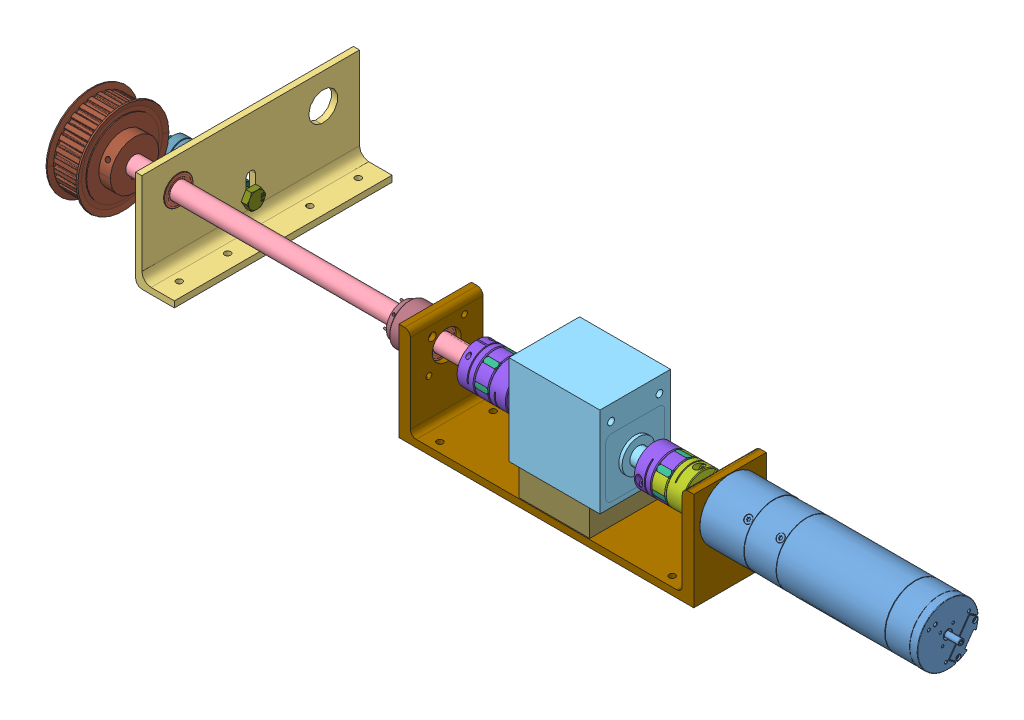
SolidWorks assembly motor assm2, configuration Default. Lengths in mm.
Overall size (903.62 127.5 242.79).
29 component instances, 17 part files, 53 mates.
Components (placement in the parent):
- motor v1-1: motor v1 [Default] at (-10.682 -0.6 0) x (1 0 0) z (0 -0.707107 0.707107) size (278.16 78.2 78.2)
- vbx_18mmID_bearing-1: vbx_18mmID_bearing [5972K329] at (-306.982 -0.6 0) x (0 0 1) z (1 0 0) size (30 30 7)
- vbx_18mmID_bearing-2: vbx_18mmID_bearing [5972K329] at (-304.0556 -36.1833 21.8955) x (0 0.990942 0.13429) z (-1 0 0) size (30 30 7)
- vbx_18mmID_bearing-3: vbx_18mmID_bearing [5972K329] at (-578.9992 -0.6 0) x (0 -0.254277 0.967131) z (1 0 0) size (30 30 7)
- bearing mount-3: bearing mount [Default] at (-582.4992 -70.6 -187.5) x (0 0 1) z (-1 0 0) size (225 101.6 40)
- 1439K370_1045 CARBON STEEL KEYED ROTARY SHAFT-1: 1439K370_1045 CARBON STEEL KEYED ROTARY SHAFT [1439K37] at (-457.6492 -0.6 0) x (0 0 1) z (1 0 0) size (18 17.49 425)
- Torque sensor-1: Torque sensor [Default] at (-150.7086 -0.6 0) x (0 0 -1) z (1 0 0) size (73 93 168)
- 15-18mm Misalinemnt coupler-1: 15-18mm Misalinemnt coupler [Default] at (-34.8408 -7.0529 -26.7672) x (0 -0.707107 0.707107) z (-1 0 0) size (41.3 42.02 51.03)
  - 9845T210_VIBRATE-DAMPING PRECISION FLEXIBLE SHAFT CPLG-1: 9845T210_VIBRATE-DAMPING PRECISION FLEXIBLE SHAFT CPLG [9845T21] at (14.3644 23.4902 31.8678) size (38.38 42 16.93)
  - 9845T469_VIBRATE-DAMPING PRECISION FLEXIBLE SHAFT COUPLING-1: 9845T469_VIBRATE-DAMPING PRECISION FLEXIBLE SHAFT COUPLING [9845T469] at (14.3644 23.4902 25.3411) size (41.3 41.3 33.46)
  - 9845T471_VIBRATE-DAMPING PRECISION FLEXIBLE SHAFT COUPLING-1: 9845T471_VIBRATE-DAMPING PRECISION FLEXIBLE SHAFT COUPLING [9845T471] at (14.3644 23.4902 23.3678) x (-1 0 0) z (0 0 -1) size (41.3 41.3 33.46)
- 1630T721_MULTIPURPOSE 6061 ALUMINUM U-CHANNEL-1: 1630T721_MULTIPURPOSE 6061 ALUMINUM U-CHANNEL [1630T721] at (-158.082 -70.6 0) size (304.8 101.6 75)
- 18-18mm Misalinemnt coupler-1: 18-18mm Misalinemnt coupler [Default] at (-266.5764 13.7644 23.4902) x (0 -1 0) z (1 0 0) size (41.3 42.02 51.03)
  - 9845T210_VIBRATE-DAMPING PRECISION FLEXIBLE SHAFT CPLG-1: 9845T210_VIBRATE-DAMPING PRECISION FLEXIBLE SHAFT CPLG [9845T21] at (14.3644 23.4902 31.8678) size (38.38 42 16.93)
  - 9845T471_VIBRATE-DAMPING PRECISION FLEXIBLE SHAFT COUPLING-1: 9845T471_VIBRATE-DAMPING PRECISION FLEXIBLE SHAFT COUPLING [9845T471] at (14.3644 23.4902 23.3678) x (-1 0 0) z (0 0 -1) size (41.3 41.3 33.46)
  - 9845T471_VIBRATE-DAMPING PRECISION FLEXIBLE SHAFT COUPLING-2: 9845T471_VIBRATE-DAMPING PRECISION FLEXIBLE SHAFT COUPLING [9845T471] at (14.3644 23.4902 25.3411) size (41.3 41.3 33.46)
- Encoder v1-1: Encoder v1 [Default] at (-285.7992 -0.6 0) x (0 -0.379337 0.925259) z (-1 0 0) size (50.8 52.34 36.53) (hidden)
- 28tooth-1: 28tooth [Default] at (-665.1492 -0.6 0) x (1 0 0) z (0 0 -1) size (44.41 95 95) (flexible)
  - ATPA28L100_B_N18_3-1: ATPA28L100_B_N18_3 [Default] at (38 -4.5 -7.7942) x (0 0.5 0.866025) z (-1 0 0) size (5 6 6)
  - ATPA28L100_B_N18_3-2: ATPA28L100_B_N18_3 [Default] at (38 11.8 0) x (0 -1 0) z (-1 0 0) size (5 6 6)
  - ATPA28L100_B_N18_6-1: ATPA28L100_B_N18_6 [Default] at origin size (44.41 95 95)
- Torque sensor spacer-1: Torque sensor spacer [Default] at (-150.7086 -36.1 0) x (-1 0 0) z (0 0 1) size (73 27.73 73)
- Through Hole Slip ring H2042-06s-1: Through Hole Slip ring H2042-06s [Default] at (-330.4544 -0.6 0) x (1 0 0) z (0 0.707107 0.707107) size (51.5 61 42)
- 5972K326_BALL BEARING-1: 5972K326_BALL BEARING [5972K326] at (-642.6055 -43.725 -75) x (0 -0.044078 -0.999028) z (1 0 0) size (30 30 9)
- 90593A008_BLACK-OXIDE STEEL HEX NUT-1: 90593A008_BLACK-OXIDE STEEL HEX NUT [90593A008] at (-586.4992 -43.725 -75) x (0 1 0) z (0 0 1) size (17 8 19.63)
- 91310A139_HIGH-STRG UNCOATED STL CAP SCREW - CLASS 10.9-1: 91310A139_HIGH-STRG UNCOATED STL CAP SCREW - CLASS 10.9 [91310A139] at (-617.9492 -43.725 -75) x (-1 0 0) z (0 -1 0) size (96.4 19.63 17)
- 90593A008_BLACK-OXIDE STEEL HEX NUT-2: 90593A008_BLACK-OXIDE STEEL HEX NUT [90593A008] at (-634.1055 -43.725 -75) x (0 1 0) z (0 0 1) size (17 8 19.63)
- 90593A008_BLACK-OXIDE STEEL HEX NUT-3: 90593A008_BLACK-OXIDE STEEL HEX NUT [90593A008] at (-660.1055 -43.725 -75) x (0 -0.5 0.866025) z (0 0.866025 0.5) size (17 8 19.63)
- 5972K326_BALL BEARING-2: 5972K326_BALL BEARING [5972K326] at (-651.6055 -43.725 -75) x (0 -0.044078 -0.999028) z (1 0 0) size (30 30 9)
Mates (geometry in assembly coordinates):
- Concentric25: concentric anti-aligned: cylinder of vbx_18mmID_bearing-1 through (-303.482 -0.6 0) axis (1 0 0) radius 9; cylinder of 1439K611_1045 CARBON STEEL KEYED ROTARY SHAFT (1)-1 through (-34.75 0 0) axis (-1 0 0) radius 10
- Parallel10: parallel anti-aligned: plane of vbx_18mmID_bearing-1 through (-306.982 -0.6 0) normal (0 -1 0); plane of 1439K611_1045 CARBON STEEL KEYED ROTARY SHAFT (1)-1 through (-334.75 -3 10) normal (0 1 0)
- Concentric26: concentric anti-aligned: cylinder of 1439K611_1045 CARBON STEEL KEYED ROTARY SHAFT (1)-1 through (-34.75 0 0) axis (-1 0 0) radius 10; cylinder of timming belt pully-1/timing belt pully face-2 through (-119.9209 0 0) axis (1 0 0) radius 10
- Parallel12: parallel anti-aligned: plane of 1439K611_1045 CARBON STEEL KEYED ROTARY SHAFT (1)-1 through (-334.75 -3 10) normal (0 1 0); plane of timming belt pully-1/timing belt pully face-1 through (-158.0209 -2.95 0) normal (0 -1 0)
- Concentric30: concentric aligned: cylinder of 1439K611_1045 CARBON STEEL KEYED ROTARY SHAFT (1)-1 through (-34.75 0 0) axis (-1 0 0) radius 10; cylinder of vbx_18mmID_bearing-2 through (-307.5556 -36.1833 21.8955) axis (-1 0 0) radius 9
- Coincident43: coincident aligned: plane of vbx_18mmID_bearing-3 through (-582.4992 -14.7685 -3.7252) normal (-1 0 0); plane of bearing mount-3 through (-582.4992 -70.6 37.5) normal (-1 0 0)
- Concentric38: concentric aligned: cylinder of motor v1-1 through (-15.882 -0.6 0) axis (-1 0 0) radius 7.5; cylinder of 1439K370_1045 CARBON STEEL KEYED ROTARY SHAFT-1 through (-245.1492 -0.6 0) axis (-1 0 0) radius 9
- Concentric39: concentric aligned: cylinder of motor v1-1 through (-15.882 -0.6 0) axis (-1 0 0) radius 7.5; cylinder of Torque sensor-1 through (-66.7086 -0.6 0) axis (-1 0 0) radius 9
- Parallel13: parallel aligned: plane of Torque sensor-1 through (-103.7086 56.9 36.5) normal (0 0 1)
- Concentric50: concentric anti-aligned: cylinder of motor v1-1 through (-15.882 -0.6 0) axis (-1 0 0) radius 7.5; cylinder of 15-18mm Misalinemnt coupler-1/9845T469_VIBRATE-DAMPING PRECISION FLEXIBLE SHAFT COUPLING-1 through (-78.682 -0.6 0) axis (1 0 0) radius 7.5
- Coincident48: coincident anti-aligned: plane of motor v1-1 through (-39.182 -7.6711 3.5355) normal (0 -0.707107 -0.707107); plane of 15-18mm Misalinemnt coupler-1/9845T469_VIBRATE-DAMPING PRECISION FLEXIBLE SHAFT COUPLING-1 through (-33.682 -8.2368 4.1012) normal (0 0.707107 0.707107)
- Coincident49: coincident aligned: plane of 15-18mm Misalinemnt coupler-1/9845T469_VIBRATE-DAMPING PRECISION FLEXIBLE SHAFT COUPLING-1 through (-44.682 -0.6 -29.2035) normal (-1 0 0); plane of motor v1-1 through (-44.682 2.087 2.687) normal (-1 0 0)
- Coincident50: coincident aligned: plane of Torque sensor-1 through (-66.7086 -0.6 0) normal (1 0 0); plane of 15-18mm Misalinemnt coupler-1/9845T471_VIBRATE-DAMPING PRECISION FLEXIBLE SHAFT COUPLING-1 through (-66.7086 -0.6 0) normal (1 0 0)
- Concentric51: concentric aligned: cylinder of motor v1-1 through (-7.932 -0.6 0) axis (1 0 0) radius 20; cylinder of 1630T721_MULTIPURPOSE 6061 ALUMINUM U-CHANNEL-1 through (-26.682 -0.6 0) axis (1 0 0) radius 21
- Concentric52: concentric aligned: cylinder of motor v1-1 through (0.818 17.7848 18.3848) axis (-1 0 0) radius 2.067; cylinder of 1630T721_MULTIPURPOSE 6061 ALUMINUM U-CHANNEL-1 through (-17.62 17.7848 18.3848) axis (-1 0 0) radius 2.65
- Concentric53: concentric aligned: cylinder of vbx_18mmID_bearing-1 through (-303.482 -0.6 0) axis (1 0 0) radius 15; cylinder of 1630T721_MULTIPURPOSE 6061 ALUMINUM U-CHANNEL-1 through (-319.544 -0.6 0) axis (1 0 0) radius 15
- Coincident54: coincident anti-aligned: plane of motor v1-1 through (-5.682 -18.808 18.208) normal (-1 0 0); plane of 1630T721_MULTIPURPOSE 6061 ALUMINUM U-CHANNEL-1 through (-5.682 -70.6 37.5) normal (1 0 0)
- Coincident55: coincident aligned: plane of vbx_18mmID_bearing-1 through (-310.482 -15.25 0) normal (-1 0 0); plane of 1630T721_MULTIPURPOSE 6061 ALUMINUM U-CHANNEL-1 through (-310.482 31 37.5) normal (-1 0 0)
- Concentric54: concentric anti-aligned: cylinder of Torque sensor-1 through (-234.7086 -0.6 0) axis (1 0 0) radius 9; cylinder of 18-18mm Misalinemnt coupler-1/9845T471_VIBRATE-DAMPING PRECISION FLEXIBLE SHAFT COUPLING-1 through (-216.7086 -0.6 0) axis (-1 0 0) radius 9
- Coincident56: coincident aligned: plane of Torque sensor-1 through (-234.7086 -0.6 0) normal (-1 0 0); plane of 18-18mm Misalinemnt coupler-1/9845T471_VIBRATE-DAMPING PRECISION FLEXIBLE SHAFT COUPLING-1 through (-234.7086 -0.6 0) normal (-1 0 0)
- Coincident57: coincident aligned: plane of Torque sensor-1 through (-150.7086 5.4 -3) normal (0 0 1); plane of 18-18mm Misalinemnt coupler-1/9845T471_VIBRATE-DAMPING PRECISION FLEXIBLE SHAFT COUPLING-1 through (-216.7086 10.6853 -3) normal (0 0 1)
- Concentric55: concentric anti-aligned: cylinder of vbx_18mmID_bearing-1 through (-303.482 -0.6 0) axis (1 0 0) radius 9; cylinder of Encoder v1-1 through (-261.0342 -0.6 0) axis (-1 0 0) radius 7.5006
- Concentric56: concentric anti-aligned: cylinder of 1439K370_1045 CARBON STEEL KEYED ROTARY SHAFT-1 through (-245.1492 -0.6 0) axis (-1 0 0) radius 9; cylinder of 28tooth-1/ATPA28L100_B_N18_6-1 through (-621.1492 -0.6 0) axis (1 0 0) radius 9
- Coincident59: coincident aligned: plane of 1439K370_1045 CARBON STEEL KEYED ROTARY SHAFT-1 through (-670.1492 -9.6 3) normal (0 0 -1); plane of 28tooth-1/ATPA28L100_B_N18_6-1 through (-621.1492 -0.6 3) normal (0 0 -1)
- Coincident61: coincident anti-aligned: plane of Torque sensor-1 through (-103.7086 -36.1 36.5) normal (0 -1 0); plane of Torque sensor spacer-1 through (-150.7086 -36.1 0) normal (0 1 0)
- Concentric59: concentric anti-aligned: cylinder of Torque sensor-1 through (-177.2086 -36.1 26.5) axis (0 -1 0) radius 3.5; cylinder of Torque sensor spacer-1 through (-177.2086 -63.834 26.5) axis (0 1 0) radius 4.1
- Concentric60: concentric anti-aligned: circle of Torque sensor-1; cylinder of Torque sensor spacer-1 through (-124.2086 -63.834 26.5) axis (0 1 0) radius 4.1
- Distance5: distance = 5 mm aligned: plane of 28tooth-1/ATPA28L100_B_N18_6-1 through (-665.1492 -0.6 0) normal (-1 0 0); plane of 1439K370_1045 CARBON STEEL KEYED ROTARY SHAFT-1 through (-670.1492 -0.6 0) normal (-1 0 0)
- Concentric61: concentric anti-aligned: cylinder of vbx_18mmID_bearing-3 through (-575.4992 -0.6 0) axis (1 0 0) radius 9; cylinder of 1439K370_1045 CARBON STEEL KEYED ROTARY SHAFT-1 through (-245.1492 -0.6 0) axis (-1 0 0) radius 9
- Distance6: distance = 45 mm aligned: plane of 28tooth-1/ATPA28L100_B_N18_6-1 through (-621.1492 -25.6 0) normal (1 0 0); plane of bearing mount-3 through (-576.1492 31 37.5) normal (1 0 0)
- Coincident64: coincident anti-aligned: plane of 1439K370_1045 CARBON STEEL KEYED ROTARY SHAFT-1 through (-245.1492 -0.6 0) normal (1 0 0); plane of 18-18mm Misalinemnt coupler-1/9845T210_VIBRATE-DAMPING PRECISION FLEXIBLE SHAFT CPLG-1 through (-245.1492 -0.6 0) normal (-1 0 0)
- Coincident65: coincident aligned: plane of 1439K370_1045 CARBON STEEL KEYED ROTARY SHAFT-1 through (-670.1492 -9.6 -3) normal (0 0 1); plane of 18-18mm Misalinemnt coupler-1/9845T471_VIBRATE-DAMPING PRECISION FLEXIBLE SHAFT COUPLING-2 through (-267.7353 -11.8853 -3) normal (0 0 1)
- Coincident70: coincident aligned: plane of bearing mount-3 through (-542.4992 -70.6 37.5) normal (0 -1 0); plane of 1630T721_MULTIPURPOSE 6061 ALUMINUM U-CHANNEL-1 through (-310.482 -70.6 37.5) normal (0 -1 0)
- Concentric70: concentric aligned: cylinder of 1439K370_1045 CARBON STEEL KEYED ROTARY SHAFT-1 through (-245.1492 -0.6 0) axis (-1 0 0) radius 9; cylinder of Through Hole Slip ring H2042-06s-1 through (-343.482 -0.6 0) axis (-1 0 0) radius 10
- Coincident82: coincident anti-aligned: plane of 1630T721_MULTIPURPOSE 6061 ALUMINUM U-CHANNEL-1 through (-310.482 31 37.5) normal (-1 0 0); plane of Through Hole Slip ring H2042-06s-1 through (-310.482 17.4312 -18.0312) normal (1 0 0)
- Tangent1: tangent anti-aligned: cylinder of 1630T721_MULTIPURPOSE 6061 ALUMINUM U-CHANNEL-1 through (-287.2303 17.7848 -18.3848) axis (-1 0 0) radius 3; plane of Through Hole Slip ring H2042-06s-1 through (-310.482 19.5525 -15.9099) normal (0 -0.707107 -0.707107)
- Concentric71: concentric aligned: cylinder of 1439K370_1045 CARBON STEEL KEYED ROTARY SHAFT-1 through (-245.1492 -0.6 0) axis (-1 0 0) radius 9; cylinder of bearing mount-3 through (-507.4992 -0.6 0) axis (-1 0 0) radius 15
- Slot1: slot anti-aligned: plane of bearing mount-3 through (-586.1492 -25.725 -70) normal (0 0 -1); cylinder of 91310A139_HIGH-STRG UNCOATED STL CAP SCREW - CLASS 10.9-1 through (-576.1492 -43.725 -75) axis (-1 0 0) radius 5; cylinder of bearing mount-3 through (-586.1492 -25.725 -75) axis (1 0 0) radius 5
- Coincident83: coincident anti-aligned: plane of bearing mount-3 through (-576.1492 31 37.5) normal (1 0 0); plane of 91310A139_HIGH-STRG UNCOATED STL CAP SCREW - CLASS 10.9-1 through (-576.1492 -35.225 -70.0925) normal (-1 0 0)
- Concentric72: concentric anti-aligned: cylinder of 90593A008_BLACK-OXIDE STEEL HEX NUT-1 through (-590.4992 -43.725 -75) axis (1 0 0) radius 5; cylinder of 91310A139_HIGH-STRG UNCOATED STL CAP SCREW - CLASS 10.9-1 through (-576.1492 -43.725 -75) axis (-1 0 0) radius 5
- Coincident84: coincident anti-aligned: plane of bearing mount-3 through (-582.4992 -70.6 37.5) normal (-1 0 0); plane of 90593A008_BLACK-OXIDE STEEL HEX NUT-1 through (-582.4992 -52.225 -79.9075) normal (1 0 0)
- Concentric73: concentric anti-aligned: cylinder of 5972K326_BALL BEARING-1 through (-638.1055 -43.725 -75) axis (1 0 0) radius 5; cylinder of 91310A139_HIGH-STRG UNCOATED STL CAP SCREW - CLASS 10.9-1 through (-576.1492 -43.725 -75) axis (-1 0 0) radius 5
- Concentric74: concentric anti-aligned: cylinder of 91310A139_HIGH-STRG UNCOATED STL CAP SCREW - CLASS 10.9-1 through (-576.1492 -43.725 -75) axis (-1 0 0) radius 5; cylinder of 90593A008_BLACK-OXIDE STEEL HEX NUT-2 through (-638.1055 -43.725 -75) axis (1 0 0) radius 5
- Concentric75: concentric aligned: cylinder of 91310A139_HIGH-STRG UNCOATED STL CAP SCREW - CLASS 10.9-1 through (-576.1492 -43.725 -75) axis (-1 0 0) radius 5; cylinder of 90593A008_BLACK-OXIDE STEEL HEX NUT-3 through (-656.1055 -43.725 -75) axis (-1 0 0) radius 5
- Coincident86: coincident anti-aligned: circle of 28tooth-1/ATPA28L100_B_N18_6-1; plane of 90593A008_BLACK-OXIDE STEEL HEX NUT-3 through (-664.1055 -43.725 -84.815) normal (-1 0 0)
- Concentric76: concentric anti-aligned: cylinder of 91310A139_HIGH-STRG UNCOATED STL CAP SCREW - CLASS 10.9-1 through (-576.1492 -43.725 -75) axis (-1 0 0) radius 5; cylinder of 5972K326_BALL BEARING-2 through (-647.1055 -43.725 -75) axis (1 0 0) radius 5
- Coincident87: coincident anti-aligned: plane of 5972K326_BALL BEARING-1 through (-647.1055 -29.1891 -75.6413) normal (-1 0 0); plane of 5972K326_BALL BEARING-2 through (-647.1055 -29.1891 -75.6413) normal (1 0 0)
- Coincident88: coincident anti-aligned: plane of 90593A008_BLACK-OXIDE STEEL HEX NUT-3 through (-656.1055 -43.725 -84.815) normal (1 0 0); plane of 5972K326_BALL BEARING-2 through (-656.1055 -29.1891 -75.6413) normal (-1 0 0)
- Coincident89: coincident anti-aligned: plane of 5972K326_BALL BEARING-1 through (-638.1055 -34.6569 -75.4001) normal (1 0 0); plane of 90593A008_BLACK-OXIDE STEEL HEX NUT-2 through (-638.1055 -52.225 -79.9075) normal (-1 0 0)
- Coincident90: coincident aligned: plane of 91310A139_HIGH-STRG UNCOATED STL CAP SCREW - CLASS 10.9-1 through (-569.7492 -35.225 -79.9075) normal (0 1 0); plane of 90593A008_BLACK-OXIDE STEEL HEX NUT-1 through (-590.4992 -35.225 -70.0925) normal (0 1 0)
- Coincident91: coincident aligned: plane of 90593A008_BLACK-OXIDE STEEL HEX NUT-1 through (-590.4992 -35.225 -70.0925) normal (0 1 0); plane of 90593A008_BLACK-OXIDE STEEL HEX NUT-2 through (-638.1055 -35.225 -70.0925) normal (0 1 0)
- Coincident92: coincident aligned: plane of 90593A008_BLACK-OXIDE STEEL HEX NUT-2 through (-638.1055 -35.225 -70.0925) normal (0 1 0); plane of 90593A008_BLACK-OXIDE STEEL HEX NUT-3 through (-656.1055 -35.225 -79.9075) normal (0 1 0)
- Parallel14: parallel aligned: plane of bearing mount-3 through (-582.4992 31 37.5) normal (0 1 0); plane of 91310A139_HIGH-STRG UNCOATED STL CAP SCREW - CLASS 10.9-1 through (-569.7492 -35.225 -79.9075) normal (0 1 0)
